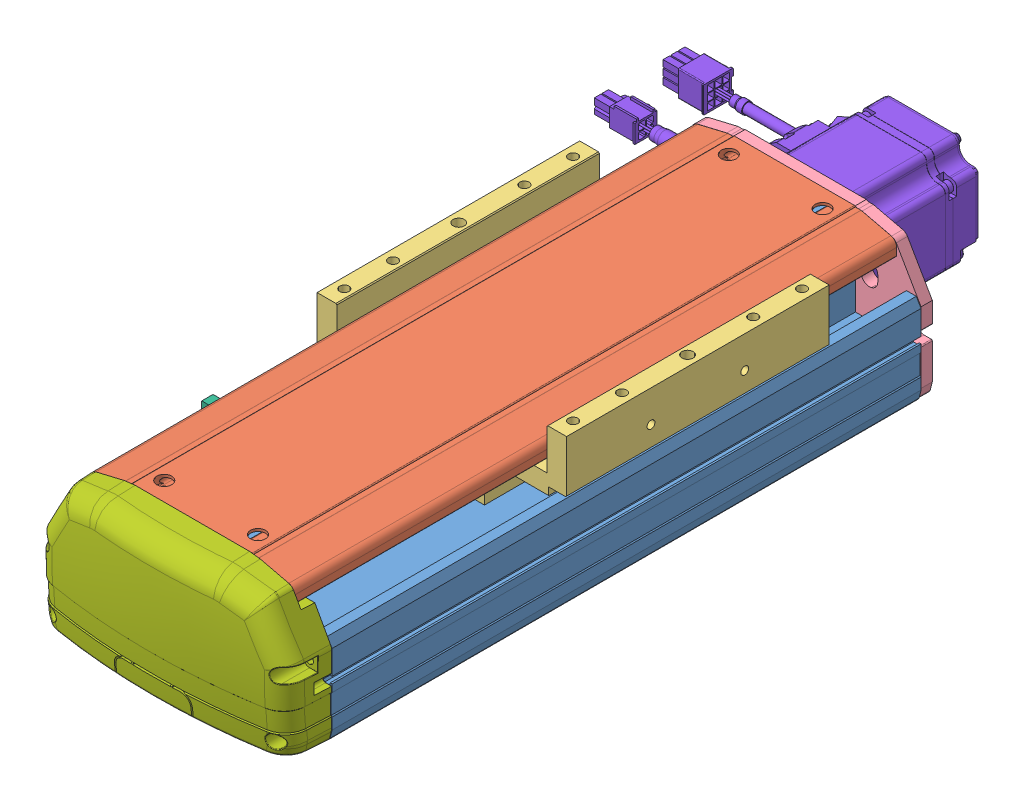
SolidWorks assembly S14-BC-200W, configuration 默认. Lengths in mm.
Overall size (186.7 78.03 415).
10 component instances, 8 part files, 29 mates.
Components (placement in the parent):
- S14-BC-底座^S14-BC-200W-1: S14-BC-底座^S14-BC-200W [默认] at origin size (135 67.23 337) (virtual)
- S14-BC上盖^S14-BC-200W-1: S14-BC上盖^S14-BC-200W [默认] at (0 61 0) size (109 12.5 321) (virtual)
- S14-BRSFSR16滑座^S14-BC-200W-1: S14-BRSFSR16滑座^S14-BC-200W [默认] at (-1.39 35.7784 98) size (133 62 140) (virtual)
- 复件 电机板S13-14-BC-60^S14-BC-200W-1: 复件 电机板S13-14-BC-60^S14-BC-200W [默认] at (0 1.7 -6) size (135 72.5 6) (virtual)
- 复件 外置感应片ST14-17^S14-BC-200W-1: 复件 外置感应片ST14-17^S14-BC-200W [默认] at (-67.4964 55 118) x (0 0 1) z (-1 0 0) size (70 30.4 7.7) (virtual)
- 复件 光电开关EE-SX672^S14-BC-200W-1: 复件 光电开关EE-SX672^S14-BC-200W [默认] at (-67.5 19.74 102) x (0 0 1) z (-1 0 0) size (26 25 13) (virtual)
- 复件 光电开关EE-SX672^S14-BC-200W-2: 复件 光电开关EE-SX672^S14-BC-200W [默认] at (-67.5 19.74 128) x (0 0 1) z (-1 0 0) size (26 25 13) (virtual)
- 复件 光电开关EE-SX672^S14-BC-200W-3: 复件 光电开关EE-SX672^S14-BC-200W [默认] at (-67.5 19.74 229.5) x (0 0 1) z (-1 0 0) size (26 25 13) (virtual)
- 复件 (2) 13-14塑胶端盖^S14-BC-200W-1: 复件 (2) 13-14塑胶端盖^S14-BC-200W [Default] at (0 1 334) x (-1 0 0) z (0 0 -1) size (134.5 73.26 30.08) (virtual)
- 复件 复件 松下200W电机MHMF022L1U22^S14-BC-200W-1: 复件 复件 松下200W电机MHMF022L1U22^S14-BC-200W [默认] at (0 35.4 0) x (0 0 1) z (0 -1 0) size (101 149.2 60) (virtual)
Mates (geometry in assembly coordinates):
- 距离10: distance = 73.5 mm: plane of S14-BC上盖^S14-BC-200W-1 through (-32 73.5 321) normal (0 1 0); plane of S14-BC-底座^S14-BC-200W-1 through (-65.3077 0 337) normal (0 -1 0)
- 距离16: distance = 1.39 mm: plane of S14-BRSFSR16滑座^S14-BC-200W-1 through (-1.39 35.7784 98) normal (1 0 0); plane of S14-BC-底座^S14-BC-200W-1 through (0 0 0) normal (1 0 0)
- 重合155: coincident: plane of S14-BC-底座^S14-BC-200W-1 through (0 0 0) normal (1 0 0); plane of S14-BC上盖^S14-BC-200W-1 through (0 61 0) normal (1 0 0)
- 距离12: distance = 78 mm: plane of S14-BRSFSR16滑座^S14-BC-200W-1 through (66.5036 78 48) normal (0 1 0); plane of S14-BC-底座^S14-BC-200W-1 through (-65.3077 0 337) normal (0 -1 0)
- 重合161: coincident: plane of S14-BC-底座^S14-BC-200W-1 through (0 0 0) normal (1 0 0); plane of assembly through (0 0 0) normal (1 0 0)
- 重合162: coincident: plane of S14-BC-底座^S14-BC-200W-1 through (0 0 0) normal (0 1 0); plane of assembly through (0 0 0) normal (0 1 0)
- 重合163: coincident: plane of S14-BC-底座^S14-BC-200W-1 through (0 0 0) normal (0 0 1); plane of assembly through (0 0 0) normal (0 0 1)
- 宽度4: width: plane of S14-BC-底座^S14-BC-200W-1 through (-67.5 12 337) normal (-1 0 0); plane of S14-BC-底座^S14-BC-200W-1 through (67.5 12 337) normal (1 0 0); plane of 复件 电机板S13-14-BC-60^S14-BC-200W-1 through (67.5 6.7616 0) normal (1 0 0); plane of 复件 电机板S13-14-BC-60^S14-BC-200W-1 through (-67.5 6.7616 0) normal (-1 0 0)
- 距离24: distance = 0.9 mm: plane of 复件 电机板S13-14-BC-60^S14-BC-200W-1 through (-64.8855 0.9 0) normal (0 -1 0); plane of S14-BC-底座^S14-BC-200W-1 through (31 0 337) normal (0 -1 0)
- 重合176: coincident: plane of S14-BC-底座^S14-BC-200W-1 through (-56.75 26.5 0) normal (0 0 -1); plane of 复件 电机板S13-14-BC-60^S14-BC-200W-1 through (64.4731 2.9 0) normal (0 0 1)
- 同心1: concentric: cylinder of S14-BRSFSR16滑座^S14-BC-200W-1 through (-66.9964 61 93) axis (-1 0 0) radius 2.1; cylinder of 复件 外置感应片ST14-17^S14-BC-200W-1 through (-67.4964 61 93) axis (-1 0 0) radius 2.55
- 重合179: coincident: plane of S14-BRSFSR16滑座^S14-BC-200W-1 through (-66.4964 16 196.7859) normal (-1 0 0); plane of 复件 外置感应片ST14-17^S14-BC-200W-1 through (-66.4964 55 118) normal (1 0 0)
- 同心2: concentric: cylinder of S14-BRSFSR16滑座^S14-BC-200W-1 through (-66.9964 61 143) axis (-1 0 0) radius 2.1; cylinder of 复件 外置感应片ST14-17^S14-BC-200W-1 through (-67.4964 61 143) axis (-1 0 0) radius 2.55
- 重合181: coincident: plane of S14-BC-底座^S14-BC-200W-1 through (-67.5 43.67 337) normal (-1 0 0); plane of 复件 光电开关EE-SX672^S14-BC-200W-1 through (-67.5 44.74 102) normal (1 0 0)
- 距离28: distance = 19.74 mm: plane of 复件 光电开关EE-SX672^S14-BC-200W-1 through (-80.5 19.74 102) normal (0 -1 0); plane of S14-BC-底座^S14-BC-200W-1 through (-65.3077 0 337) normal (0 -1 0)
- 重合183: coincident: plane of S14-BC-底座^S14-BC-200W-1 through (-67.5 43.67 337) normal (-1 0 0); plane of 复件 光电开关EE-SX672^S14-BC-200W-2 through (-67.5 44.74 128) normal (1 0 0)
- 重合184: coincident: plane of 复件 光电开关EE-SX672^S14-BC-200W-1 through (-70 32.74 118) normal (0 0 1); plane of 复件 光电开关EE-SX672^S14-BC-200W-2 through (-70 32.74 118) normal (0 0 -1)
- 重合185: coincident: plane of 复件 光电开关EE-SX672^S14-BC-200W-1 through (-80.5 19.74 102) normal (0 -1 0); plane of 复件 光电开关EE-SX672^S14-BC-200W-2 through (-80.5 19.74 128) normal (0 -1 0)
- 距离29: distance = 102 mm: plane of 复件 光电开关EE-SX672^S14-BC-200W-1 through (-80.5 19.74 102) normal (0 0 -1); plane of S14-BC-底座^S14-BC-200W-1 through (-56.75 26.5 0) normal (0 0 -1)
- 宽度7: width: plane of 复件 光电开关EE-SX672^S14-BC-200W-1 through (-80.5 19.74 108) normal (0 0 1); plane of 复件 光电开关EE-SX672^S14-BC-200W-2 through (-80.5 19.74 128) normal (0 0 -1); plane of 复件 外置感应片ST14-17^S14-BC-200W-1 through (-74.1964 37.6 110.5) normal (0 0 -1); plane of 复件 外置感应片ST14-17^S14-BC-200W-1 through (-74.1964 53 125.5) normal (0 0 1)
- 重合187: coincident: plane of S14-BC-底座^S14-BC-200W-1 through (-67.5 43.67 337) normal (-1 0 0); plane of 复件 光电开关EE-SX672^S14-BC-200W-3 through (-67.5 44.74 229.5) normal (1 0 0)
- 重合188: coincident: plane of 复件 光电开关EE-SX672^S14-BC-200W-2 through (-80.5 19.74 128) normal (0 -1 0); plane of 复件 光电开关EE-SX672^S14-BC-200W-3 through (-80.5 19.74 229.5) normal (0 -1 0)
- 距离30: distance = 78.5 mm: plane of 复件 光电开关EE-SX672^S14-BC-200W-3 through (-80.5 19.74 235.5) normal (0 0 1); plane of S14-BC-底座^S14-BC-200W-1 through (-56 -10 314) normal (0 0 1)
- 同心3: concentric: cylinder of S14-BC-底座^S14-BC-200W-1 through (62.5 39.5 337) axis (0 0 -1) radius 1.4777; cylinder of 复件 (2) 13-14塑胶端盖^S14-BC-200W-1 through (62.5 39.5 314) axis (0 0 -1) radius 2.1
- 重合189: coincident: plane of S14-BC-底座^S14-BC-200W-1 through (75.4674 -10 314) normal (0 0 1); plane of 复件 (2) 13-14塑胶端盖^S14-BC-200W-1 through (0 1 314) normal (0 0 -1)
- 宽度8: width: plane of S14-BC-底座^S14-BC-200W-1 through (-67.5 12 337) normal (-1 0 0); plane of S14-BC-底座^S14-BC-200W-1 through (67.5 12 337) normal (1 0 0); plane of 复件 (2) 13-14塑胶端盖^S14-BC-200W-1 through (-67.25 2.8914 314) normal (-0.999048 0 0.043619); plane of 复件 (2) 13-14塑胶端盖^S14-BC-200W-1 through (67.25 46.7626 314) normal (0.999048 0 0.043619)
- 同心4: concentric: cylinder of S14-BC-底座^S14-BC-200W-1 through (0 35.4 30) axis (0 0 -1) radius 25; cylinder of 复件 复件 松下200W电机MHMF022L1U22^S14-BC-200W-1 through (0 35.4 30) axis (0 0 -1) radius 5.5
- 重合190: coincident: plane of S14-BC-底座^S14-BC-200W-1 through (-56.75 26.5 0) normal (0 0 -1); plane of 复件 复件 松下200W电机MHMF022L1U22^S14-BC-200W-1 through (-25 10.4 0) normal (0 0 1)
- 同心5: concentric: cylinder of S14-BC-底座^S14-BC-200W-1 through (24.7487 60.1487 0) axis (0 0 -1) radius 1.65; cylinder of 复件 复件 松下200W电机MHMF022L1U22^S14-BC-200W-1 through (24.7487 60.1487 -54.5) axis (0 0 -1) radius 2.25
